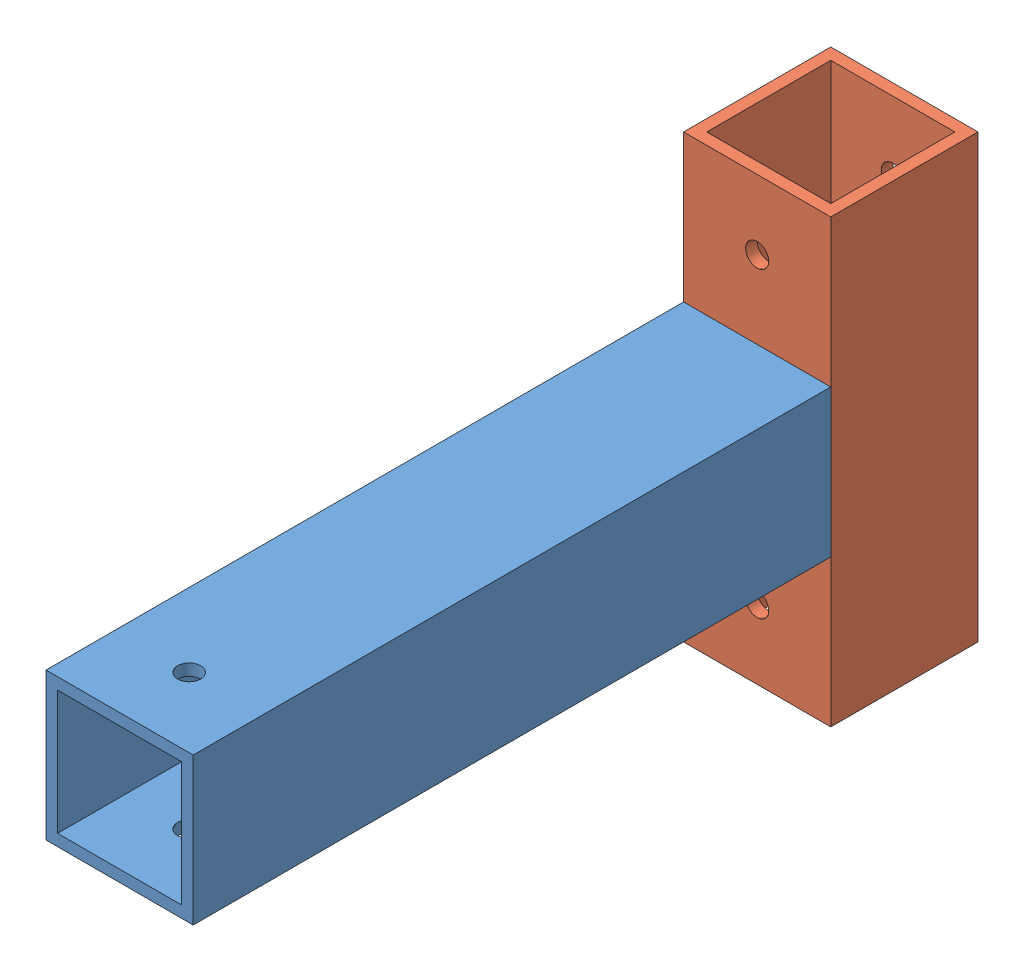
SolidWorks assembly Assem1, configuration Default. Lengths in mm.
Overall size (25.4 76.2 135.4).
2 component instances, 2 part files, 3 mates.
Components (placement in the parent):
- straightBracket-1: straightBracket [Default] at (-125.4575 19.3814 -17.2951) size (25.4 25.4 110)
- straightBracket2-1: straightBracket2 [Default] at (-125.4575 70.1814 -42.6951) x (1 0 0) z (0 -1 0) size (25.4 25.4 76.2)
Mates (geometry in assembly coordinates):
- Coincident1: coincident: plane of straightBracket-1 through (-125.4575 19.3814 -17.2951) normal (0 0 -1); plane of straightBracket2-1 through (-125.4575 -6.0186 -17.2951) normal (0 0 1)
- Coincident2: coincident: plane of straightBracket-1 through (-100.0575 19.3814 92.7049) normal (1 0 0); plane of straightBracket2-1 through (-100.0575 -6.0186 -42.6951) normal (1 0 0)
- Coincident3: coincident: moEndPointRef_w of straightBracket-1; moEndPointRef_w of straightBracket2-1
